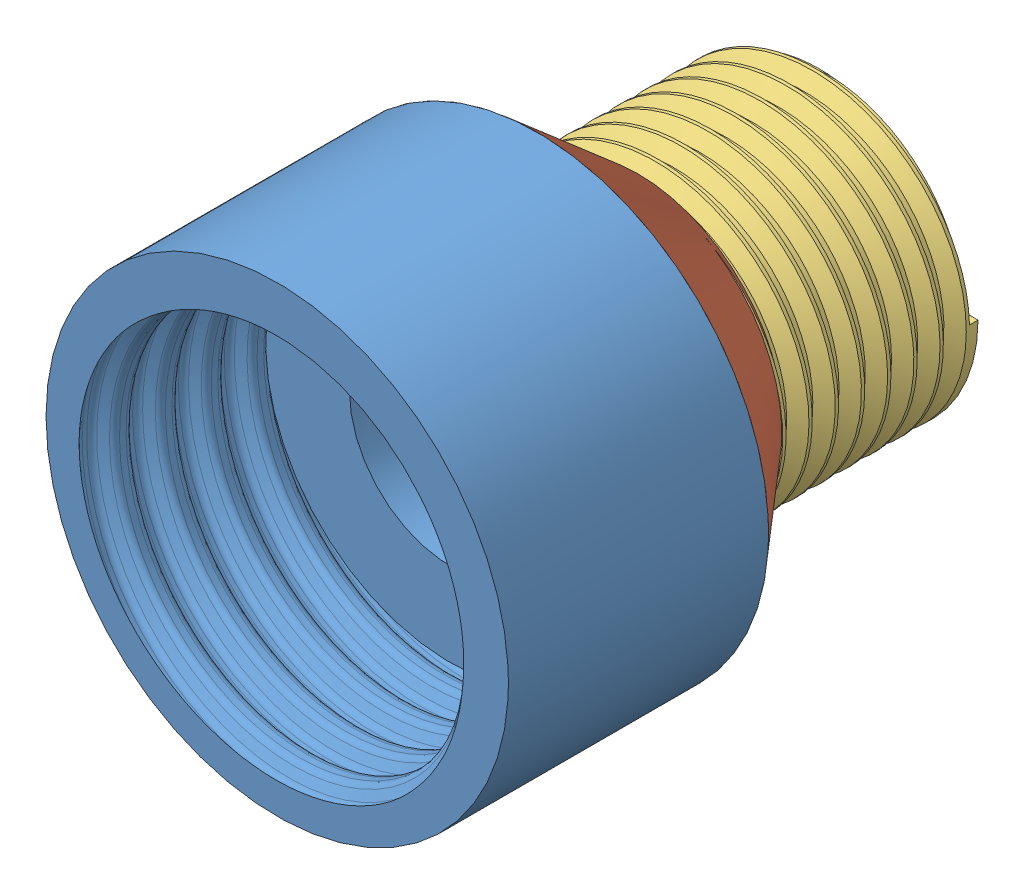
SolidWorks assembly raccord_fusee, configuration Défaut. Lengths in mm.
Overall size (38.4 38.4 42.51).
3 component instances, 3 part files, 4 mates.
Components (placement in the parent):
- raccord_goulot-1: raccord_goulot [Défaut] at (-7.578 1.9519 20.9596) size (32 32 22.08)
- cone-1: cone [Défaut] at (-7.578 1.9519 16.9467) x (-0.974172 0.225809 0) z (0.225809 0.974172 0) size (32 7 32)
- raccord_nez-1: raccord_nez [Défaut] at (-7.578 1.9519 0.9596) size (21.34 22.08 20.43)
Mates (geometry in assembly coordinates):
- Coïncidente1: coincident anti-aligned: plane of 1raccord goulot-1 through (-7.578 1.9519 20.9596) normal (0 0 -1); plane of raccord4375-1 through (-7.578 1.9519 20.9596) normal (0 0 1)
- Coaxiale1: concentric aligned: cylinder of 1raccord goulot-1 through (-7.578 1.9519 38.9596) axis (0 0 -1) radius 16; cylinder of raccord4375-1 through (-7.578 1.9519 20.9596) axis (0 0 -1) radius 10.4975
- Coïncidente2: coincident anti-aligned: plane of 1raccord goulot-1 through (-7.578 1.9519 20.9596) normal (0 0 -1); plane of cone-1 through (-7.578 1.9519 20.9596) normal (0 0 1)
- Coaxiale2: concentric aligned: cylinder of 1raccord goulot-1 through (-7.578 1.9519 38.9596) axis (0 0 -1) radius 16; cylinder of cone-1 through (-7.578 1.9519 20.9596) axis (0 0 -1) radius 7
